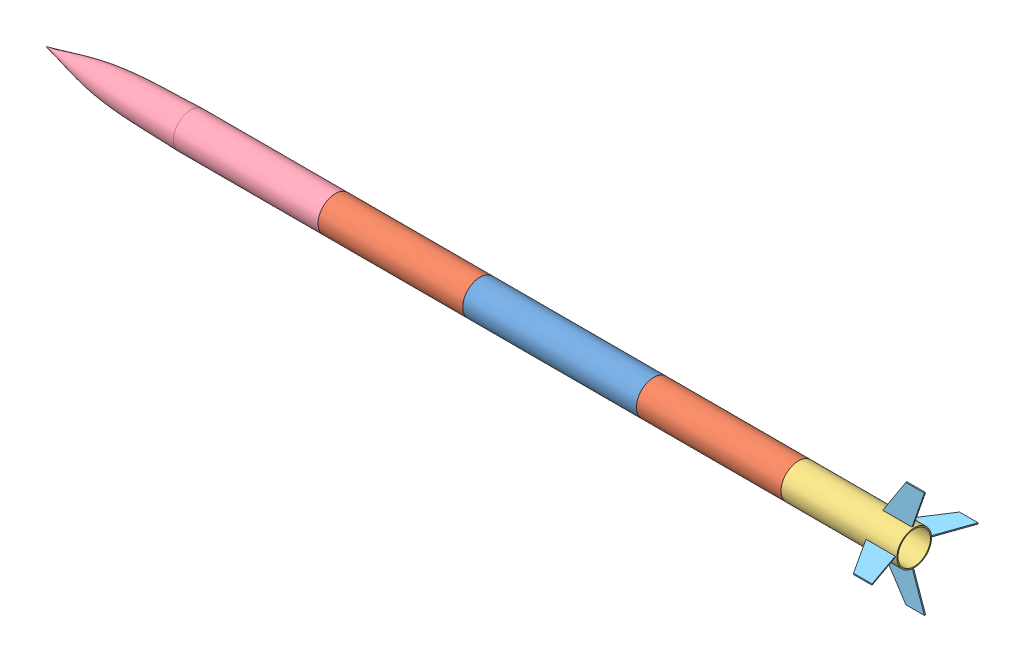
SolidWorks assembly N-2rocket, configuration ﾃﾞﾌｫﾙﾄ. Lengths in mm.
Overall size (1518.69 183.1 183.1).
9 component instances, 5 part files, 14 mates.
Components (placement in the parent):
- body_tube-1: body_tube [ﾃﾞﾌｫﾙﾄ] at (-550 0 0) size (300 60 60)
- extra_tube1-1: extra_tube1 [ﾃﾞﾌｫﾙﾄ] at (-250 0 0) size (250 60 60)
- extra_tube2-1: extra_tube2 [ﾃﾞﾌｫﾙﾄ] at origin size (200 60 60)
- nose_cone-1: nose_cone [ﾃﾞﾌｫﾙﾄ] at (-1050 0 0) size (515 60 60)
- extra_tube1-2: extra_tube1 [ﾃﾞﾌｫﾙﾄ] at (-800 0 0) size (250 60 60)
- fin-1: fin [ﾃﾞﾌｫﾙﾄ] at (145.7033 0 -28.4397) size (72.98 2 63.11)
- fin-2: fin [ﾃﾞﾌｫﾙﾄ] at (145.7033 28.4397 0) x (1 0 0) z (0 -1 0) size (72.98 2 63.11)
- fin-3: fin [ﾃﾞﾌｫﾙﾄ] at (145.7033 0 28.4397) x (1 0 0) z (0 0 -1) size (72.98 2 63.11)
- fin-4: fin [ﾃﾞﾌｫﾙﾄ] at (145.7033 -28.4397 0) x (1 0 0) z (0 1 0) size (72.98 2 63.11)
Mates (geometry in assembly coordinates):
- Coincident1: coordinate: unknown of extra_tube2-1
- Coincident2: coincident aligned: plane of extra_tube1-1 through (-250 0 0) normal (0 0 1); plane of extra_tube2-1 through (0 0 0) normal (0 0 1)
- Coincident3: coincident aligned: plane of extra_tube1-1 through (-250 0 0) normal (0 1 0); plane of extra_tube2-1 through (0 0 0) normal (0 1 0)
- Coincident4: coincident anti-aligned: plane of extra_tube1-1 through (0 0 0) normal (1 0 0); plane of extra_tube2-1 through (0 0 0) normal (-1 0 0)
- Coincident5: coincident aligned: plane of body_tube-1 through (-550 0 0) normal (0 1 0); plane of extra_tube1-1 through (-250 0 0) normal (0 1 0)
- Coincident6: coincident aligned: plane of body_tube-1 through (-550 0 0) normal (0 0 1); plane of extra_tube1-1 through (-250 0 0) normal (0 0 1)
- Coincident7: coincident anti-aligned: plane of body_tube-1 through (-250 0 0) normal (1 0 0); plane of extra_tube1-1 through (-250 0 0) normal (-1 0 0)
- Coincident8: coincident aligned: plane of body_tube-1 through (-550 0 0) normal (0 1 0); plane of extra_tube1-2 through (-800 0 0) normal (0 1 0)
- Coincident9: coincident aligned: plane of body_tube-1 through (-550 0 0) normal (0 0 1); plane of extra_tube1-2 through (-800 0 0) normal (0 0 1)
- Coincident10: coincident anti-aligned: plane of body_tube-1 through (-550 0 0) normal (-1 0 0); plane of extra_tube1-2 through (-550 0 0) normal (1 0 0)
- Coincident11: coincident aligned: plane of nose_cone-1 through (-1050 0 0) normal (0 1 0)
- Coincident12: coincident aligned: plane of nose_cone-1 through (-1050 0 0) normal (0 0 1); plane of extra_tube1-2 through (-800 0 0) normal (0 0 1)
- Coincident13: coincident anti-aligned: plane of nose_cone-1 through (-800 0 0) normal (1 0 0); plane of extra_tube1-2 through (-800 0 0) normal (-1 0 0)
- Coincident14: coincident aligned: plane of fin-1 through (145.7033 0 -28.4397) normal (0 1 0)
